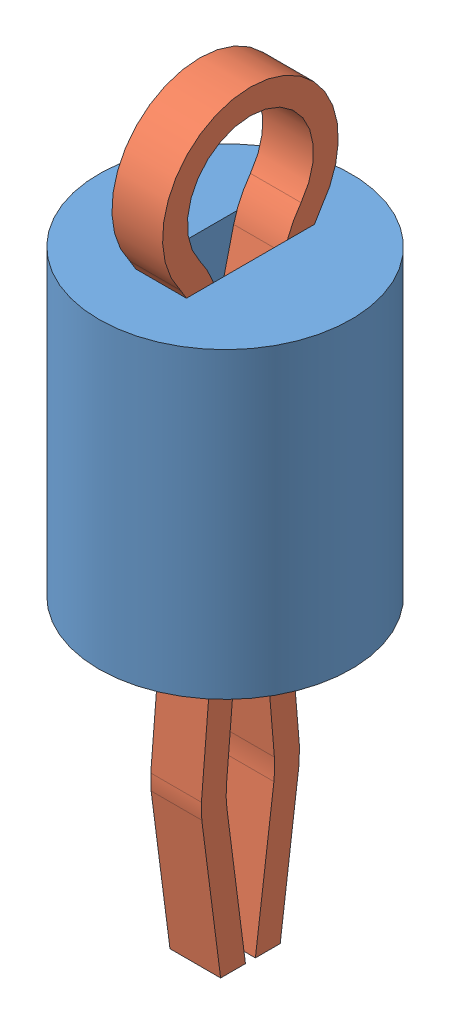
SolidWorks assembly Assem1, configuration Default. Lengths in mm.
Overall size (2.54 7.62 2.54).
2 component instances, 2 part files, 6 mates.
Components (placement in the parent):
- Spacer-red-1: Spacer-red [Default] x (0 0 1) z (0 1 0) size (2.54 2.54 3.05)
- Contact-1: Contact [Default] x (0 0 -1) z (0 1 0) size (1.77 0.51 7.62)
Mates (geometry in assembly coordinates):
- Coincident1: coincident aligned: plane of Spacer-red-1 through (0 0 0) normal (0 0 1)
- Coincident2: coincident aligned: plane of Spacer-red-1 through (0 0 0) normal (1 0 0)
- Coincident3: coincident anti-aligned: plane of Spacer-red-1 through (0 0 0) normal (0 -1 0)
- Coincident4: coincident anti-aligned: plane of Contact-1 through (0 0 0) normal (-1 0 0)
- Coincident5: coincident anti-aligned: plane of Contact-1 through (0 0 0) normal (0 0 -1)
- Distance1: distance = 3.05 mm aligned: plane of Spacer-red-1 through (0 0 0) normal (0 -1 0); plane of Contact-1 through (0 -3.05 0.175) normal (0 -1 0)
